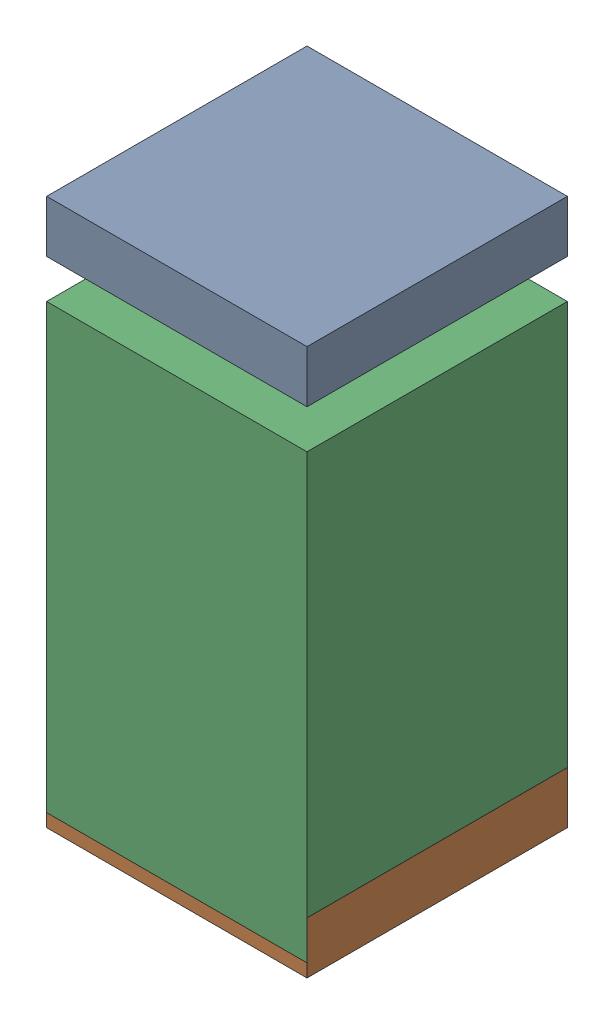
SolidWorks assembly C30, configuration Default. Lengths in mm.
Overall size (0.5 1.05 0.5).
6 component instances, 2 part files, 0 mates.
Components (placement in the parent):
- 810157360-1: 810157360 [Default] at (132.25 27.9 0) size (0.5 0.1 0.5)
  - Extruded_9-1: Extruded_9 [Default] at origin size (0.5 0.1 0.5)
- 810157360-2: 810157360 [Default] at (132.25 26.95 0) size (0.5 0.1 0.5)
  - Extruded_9-1: Extruded_9 [Default] at origin size (0.5 0.1 0.5)
- 810157104-1: 810157104 [Default] at (132.2499 27.3501 0) size (0.5 0.85 0.5)
  - Extruded_16-1: Extruded_16 [Default] at origin size (0.5 0.85 0.5)
